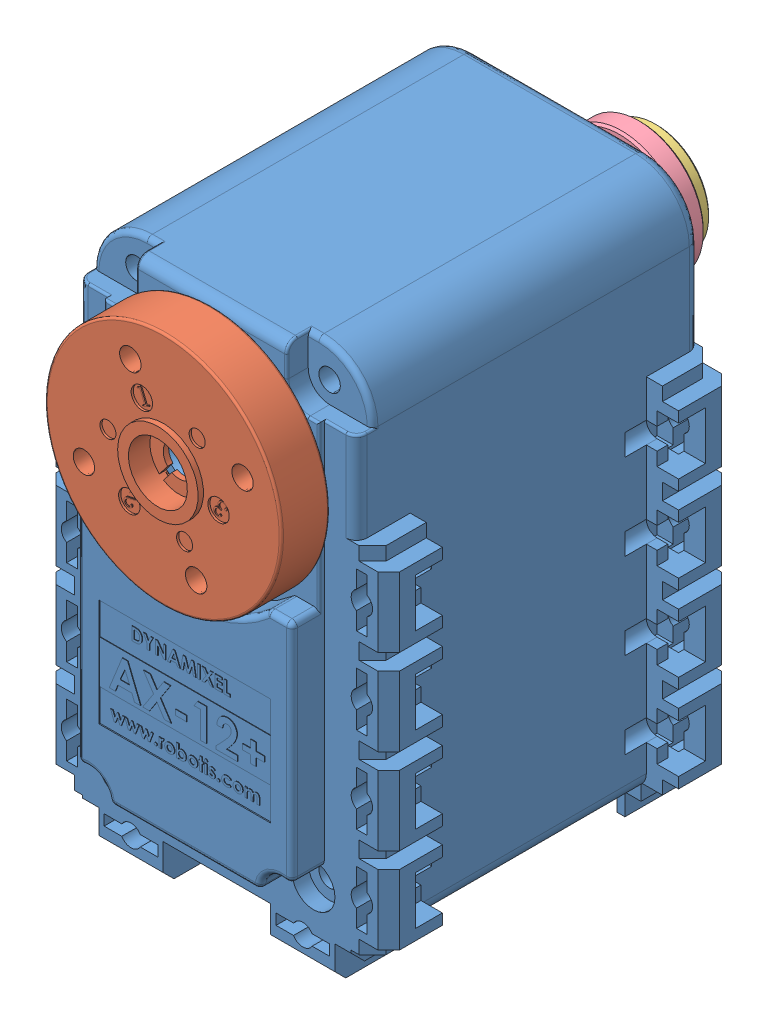
SolidWorks assembly 装配体1, configuration 默认. Lengths in mm.
Overall size (32 52.87 46.5).
4 component instances, 4 part files, 6 mates.
Components (placement in the parent):
- AX-12-1: AX-12 [默认] at (-21.4772 21.2439 34) size (32 50 38)
- RT-1: RT [默认] at (-8.4772 9.7439 71) x (-0.923728 -0.383049 0) z (0 0 -1) size (22 22 7.5)
- BU0-1: BU0 [默认] at (-8.4772 9.7439 32) x (-0.923728 -0.383049 0) z (0 0 -1) size (10 10 7)
- WA0-1: WA0 [默认] at (-8.4772 9.7439 28.5) x (-0.923728 -0.383049 0) z (0 0 -1) size (12 12 2)
Mates (geometry in assembly coordinates):
- 重合1: coincident: plane of assembly; plane of assembly; plane of AX-12-1 through (0.5228 18.2439 66.5) normal (0 0 1); plane of RT-1 through (-8.4772 9.7439 66.5) normal (0 0 -1)
- 同心1: concentric: cylinder of assembly; cylinder of assembly; cylinder of AX-12-1 through (-8.4772 9.7439 63.5) axis (0 0 1) radius 4.75; cylinder of RT-1 through (-8.4772 9.7439 66.5) axis (0 0 1) radius 11
- 重合2: coincident: plane of assembly; plane of assembly; plane of AX-12-1 through (-8.4772 9.7439 32) normal (0 0 -1); plane of BU0-1 through (-8.4772 9.7439 32) normal (0 0 1)
- 同心2: concentric: cylinder of assembly; cylinder of assembly; cylinder of AX-12-1 through (-8.4772 9.7439 33) axis (0 0 1) radius 5.5; cylinder of BU0-1 through (-8.4772 9.7439 26.5) axis (0 0 1) radius 4
- 重合3: coincident: plane of assembly; plane of assembly; plane of BU0-1 through (-8.4772 9.7439 26.5) normal (0 0 1); plane of WA0-1 through (-8.4772 9.7439 26.5) normal (0 0 -1)
- 同心3: concentric: cylinder of assembly; cylinder of assembly; cylinder of BU0-1 through (-8.4772 9.7439 26.5) axis (0 0 1) radius 4; cylinder of WA0-1 through (-8.4772 9.7439 26.5) axis (0 0 1) radius 6
